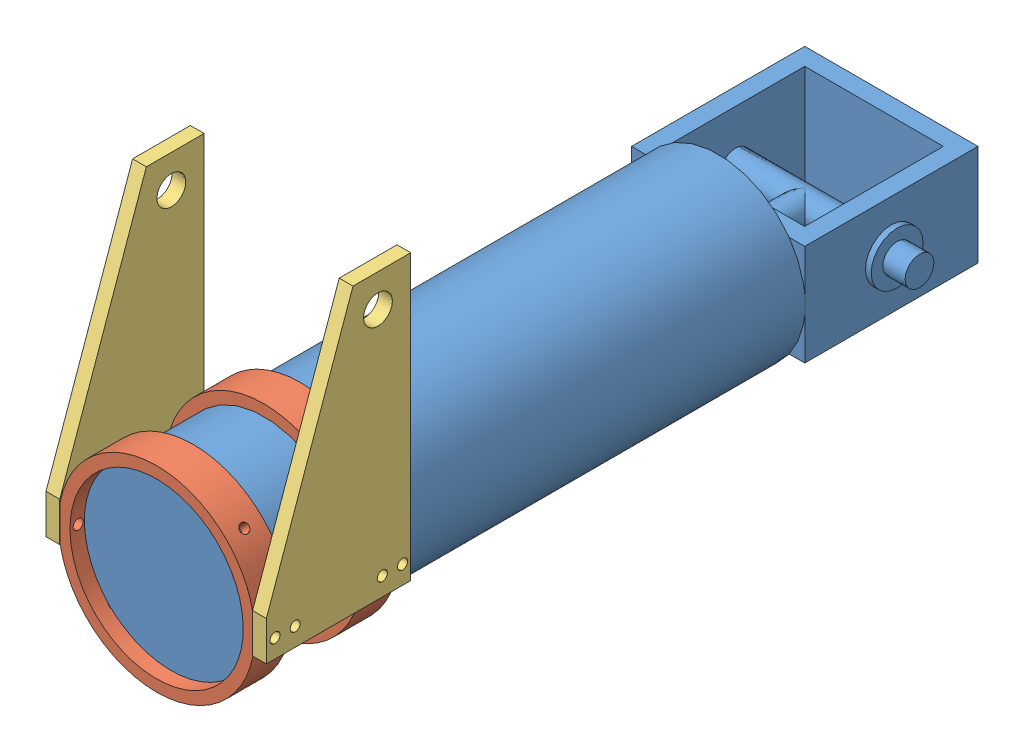
SolidWorks assembly EslabonHorizontal, configuration Predeterminado. Lengths in mm.
Overall size (96.17 140.08 254.65).
5 component instances, 3 part files, 10 mates.
Components (placement in the parent):
- EslabonSimplificado-1: EslabonSimplificado [Predeterminado] at origin size (79.5 60.33 249.5)
- SujeccionMotorV2-1: SujeccionMotorV2 [Predeterminado] at (0 0 181) x (0.707107 0.707107 0) z (0 0 1) size (68 68 12.7)
- Soporte-1: Soporte [Predeterminado] at (38.1643 -6.35 174.65) x (0 0 -1) z (-1 0 0) size (50 98.35 4.76)
- SujeccionMotorV2-2: SujeccionMotorV2 [Predeterminado] at (0 0 218.15) x (0.707107 0.707107 0) z (0 0 1) size (68 68 12.7)
- Soporte-2: Soporte [Predeterminado] at (-33.4018 -6.35 174.65) x (0 0 -1) z (-1 0 0) size (50 98.35 4.76)
Mates (geometry in assembly coordinates):
- Concéntrica2: concentric aligned: cylinder of EslabonSimplificado-1 through (0 0 30) axis (0 0 1) radius 30.165; cylinder of SujeccionMotorV2-2 through (0 0 211.8) axis (0 0 1) radius 30
- Concéntrica3: concentric aligned: cylinder of EslabonSimplificado-1 through (0 0 30) axis (0 0 1) radius 30.165; cylinder of SujeccionMotorV2-1 through (0 0 174.65) axis (0 0 1) radius 30
- Distancia1: distance = 5 mm aligned: plane of EslabonSimplificado-1 through (0 0 219.5) normal (0 0 1); plane of SujeccionMotorV2-2 through (0 0 224.5) normal (0 0 1)
- Concéntrica4: concentric anti-aligned: cylinder of Soporte-1 through (0 12.0251 57.5791) axis (0 -1 0) radius 1.75; cylinder of SujeccionMotorV2-2 through (0 -48.0833 221.65) axis (0 1 0) radius 1.75
- Concéntrica5: concentric anti-aligned: cylinder of SujeccionMotorV2-1 through (0 -48.0833 184.5) axis (0 1 0) radius 1.75; cylinder of Soporte-1 through (0 12.0251 20.4291) axis (0 -1 0) radius 1.75
- Coincidente1: coincident anti-aligned: plane of Soporte-1 through (-6.35 12.0251 10.5791) normal (0 1 0); plane of SujeccionMotorV2-2 through (6.35 -33.4018 211.8) normal (0 -1 0)
- Coincidente2: coincident anti-aligned: plane of SujeccionMotorV2-2 through (6.35 33.4018 211.8) normal (0 1 0); plane of Soporte-2 through (-6.35 33.4018 174.65) normal (0 -1 0)
- Concéntrica6: concentric anti-aligned: cylinder of SujeccionMotorV2-2 through (0 -48.0833 221.65) axis (0 1 0) radius 1.75; cylinder of Soporte-2 through (0 38.1643 221.65) axis (0 -1 0) radius 1.75
- Concéntrica7: concentric anti-aligned: cylinder of SujeccionMotorV2-1 through (0 -48.0833 184.5) axis (0 1 0) radius 1.75; cylinder of Soporte-2 through (0 38.1643 184.5) axis (0 -1 0) radius 1.75
- Paralelo5: parallel anti-aligned: plane of EslabonSimplificado-1 through (-30 -17.5 -30) normal (-1 0 0); plane of Soporte-1
